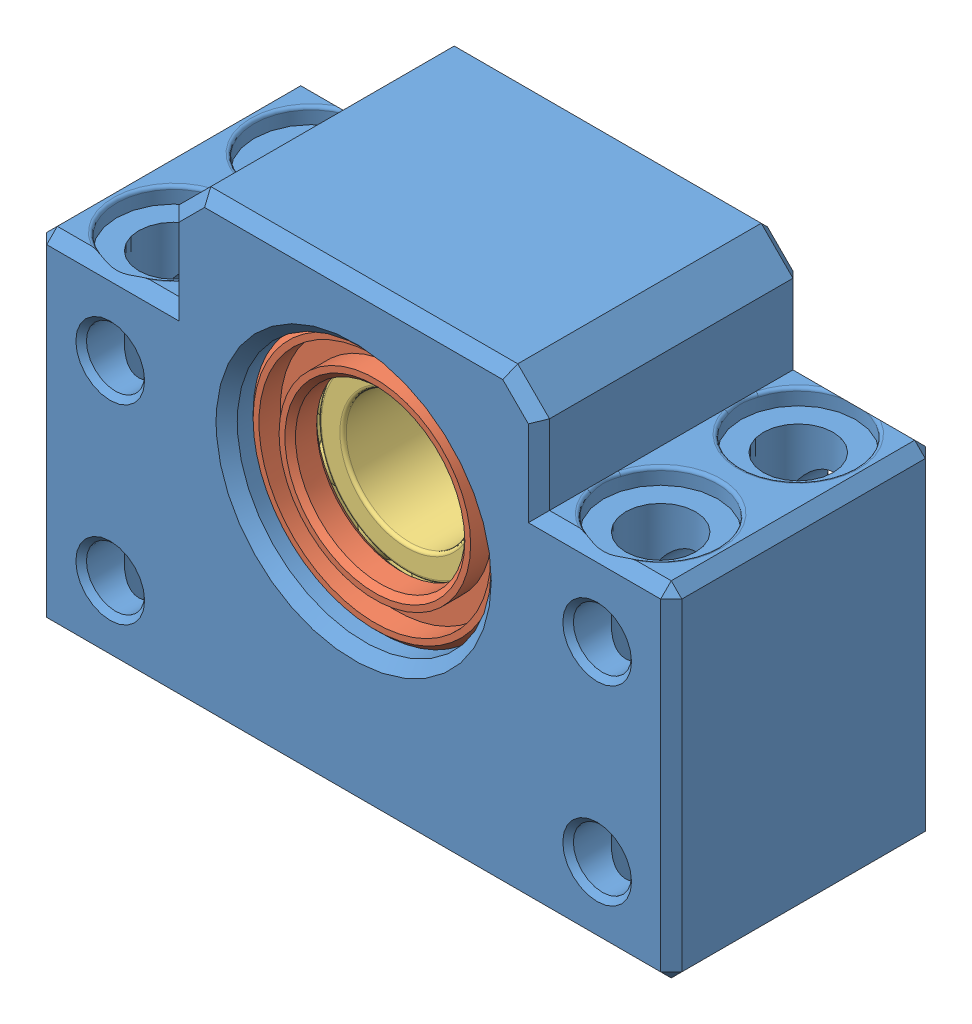
SolidWorks assembly BK12 BALLSCREW END SUPPORT, configuration Default. Lengths in mm.
Overall size (60 43 25).
5 component instances, 3 part files, 8 mates.
Components (placement in the parent):
- BK12-1-1: BK12-1 [Default] at (-11.028 26.197 -11.9785) size (60 43 25)
- BK12-2-5: BK12-2 [Default] at (-11.028 8.197 8.0215) size (24 24 3)
- 6001-Bearing-3: 6001-Bearing [Default] at (-11.028 8.197 0.0215) size (28 28 8)
- 6001-Bearing-4: 6001-Bearing [Default] at (-11.028 8.197 -7.9785) size (28 28 8)
- BK12-2-6: BK12-2 [Default] at (-11.028 8.197 -7.9785) x (-1 0 0) z (0 0 -1) size (24 24 3)
Mates (geometry in assembly coordinates):
- Concentric13: concentric: cylinder of assembly; cylinder of assembly; cylinder of BK12-1-1 through (-11.028 8.197 13.0215) axis (0 0 -1) radius 12; cylinder of BK12-2-5 through (-11.028 8.197 11.0215) axis (0 0 -1) radius 12
- Coincident11: coincident: plane of assembly; plane of assembly; plane of BK12-1-1 through (-11.028 8.197 8.0215) normal (0 0 -1); plane of BK12-2-5 through (-11.028 8.197 8.0215) normal (0 0 -1)
- Concentric14: concentric: cylinder of assembly; cylinder of assembly; cylinder of BK12-1-1 through (-11.028 8.197 8.0215) axis (0 0 -1) radius 14; cylinder of 6001-Bearing-3 through (-11.028 8.197 8.0215) axis (0 0 -1) radius 14
- Coincident12: coincident: plane of assembly; plane of assembly; plane of BK12-1-1 through (-11.028 8.197 8.0215) normal (0 0 -1); plane of 6001-Bearing-3 through (-11.028 8.197 8.0215) normal (0 0 1)
- Concentric15: concentric: cylinder of assembly; cylinder of assembly; cylinder of BK12-1-1 through (-11.028 8.197 8.0215) axis (0 0 -1) radius 14; cylinder of 6001-Bearing-4 through (-11.028 8.197 0.0215) axis (0 0 -1) radius 14
- Coincident13: coincident: plane of assembly; plane of assembly; plane of 6001-Bearing-3 through (-11.028 8.197 0.0215) normal (0 0 -1); plane of 6001-Bearing-4 through (-11.028 8.197 0.0215) normal (0 0 1)
- Concentric17: concentric: cylinder of assembly; cylinder of assembly; cylinder of BK12-1-1 through (-11.028 8.197 8.0215) axis (0 0 -1) radius 14; cylinder of BK12-2-6 through (-11.028 8.197 -10.9785) axis (0 0 1) radius 12
- Coincident15: coincident: plane of assembly; plane of assembly; plane of 6001-Bearing-4 through (-11.028 8.197 -7.9785) normal (0 0 -1); plane of BK12-2-6 through (-11.028 8.197 -7.9785) normal (0 0 1)
